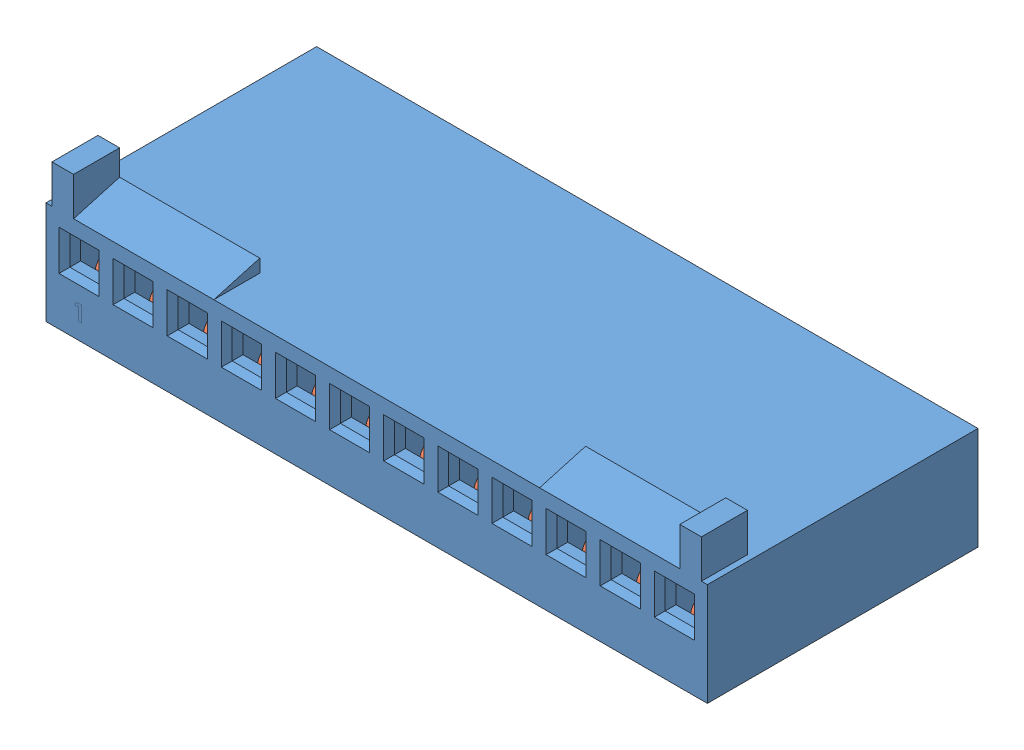
SolidWorks assembly PCB Header Connector 12x1, configuration Default. Lengths in mm.
Overall size (31.04 6.63 12.7).
13 component instances, 2 part files, 5 mates.
Components (placement in the parent):
- PCB Header Female Molex KK 254 12x1 Housing-1: PCB Header Female Molex KK 254 12x1 Housing [Default] at origin size (31.04 6.63 12.7)
- PCB Header Female KK 254 Molex Connector-2: PCB Header Female KK 254 Molex Connector [Default] at (13.97 1.0922 -11.002) size (2.11 3.68 9.73)
- PCB Header Female KK 254 Molex Connector-3: PCB Header Female KK 254 Molex Connector [Default] at (11.43 1.0922 -11.002) size (2.11 3.68 9.73)
- PCB Header Female KK 254 Molex Connector-4: PCB Header Female KK 254 Molex Connector [Default] at (8.89 1.0922 -11.002) size (2.11 3.68 9.73)
- PCB Header Female KK 254 Molex Connector-5: PCB Header Female KK 254 Molex Connector [Default] at (6.35 1.0922 -11.002) size (2.11 3.68 9.73)
- PCB Header Female KK 254 Molex Connector-6: PCB Header Female KK 254 Molex Connector [Default] at (3.81 1.0922 -11.002) size (2.11 3.68 9.73)
- PCB Header Female KK 254 Molex Connector-7: PCB Header Female KK 254 Molex Connector [Default] at (1.27 1.0922 -11.002) size (2.11 3.68 9.73)
- PCB Header Female KK 254 Molex Connector-8: PCB Header Female KK 254 Molex Connector [Default] at (-1.27 1.0922 -11.002) size (2.11 3.68 9.73)
- PCB Header Female KK 254 Molex Connector-9: PCB Header Female KK 254 Molex Connector [Default] at (-3.81 1.0922 -11.002) size (2.11 3.68 9.73)
- PCB Header Female KK 254 Molex Connector-10: PCB Header Female KK 254 Molex Connector [Default] at (-6.35 1.0922 -11.002) size (2.11 3.68 9.73)
- PCB Header Female KK 254 Molex Connector-11: PCB Header Female KK 254 Molex Connector [Default] at (-8.89 1.0922 -11.002) size (2.11 3.68 9.73)
- PCB Header Female KK 254 Molex Connector-12: PCB Header Female KK 254 Molex Connector [Default] at (-11.43 1.0922 -11.002) size (2.11 3.68 9.73)
- PCB Header Female KK 254 Molex Connector-13: PCB Header Female KK 254 Molex Connector [Default] at (-13.97 1.0922 -11.002) size (2.11 3.68 9.73)
Mates (geometry in assembly coordinates):
- Tangent11: tangent anti-aligned: plane of PCB Header Female Molex KK 254 12x1 Housing-1 through (14.732 1.0922 -0.762) normal (0 0 -1); cylinder of PCB Header Female KK 254 Molex Connector-2 through (14.945 1.8122 -1.482) axis (-1 0 0) radius 0.72
- Coincident31: coincident anti-aligned: plane of PCB Header Female Molex KK 254 12x1 Housing-1 through (14.732 1.0922 -12.7) normal (0 1 0); plane of PCB Header Female KK 254 Molex Connector-2 through (14.945 1.0922 -5.232) normal (0 -1 0)
- Parallel21: parallel anti-aligned: plane of PCB Header Female Molex KK 254 12x1 Housing-1 through (14.732 0 0) normal (-1 0 0); plane of PCB Header Female KK 254 Molex Connector-2 through (14.945 1.8122 -1.992) normal (1 0 0)
- Width1: width aligned: plane of PCB Header Female Molex KK 254 12x1 Housing-1 through (14.732 0 0) normal (-1 0 0); plane of PCB Header Female Molex KK 254 12x1 Housing-1 through (13.208 0 0) normal (1 0 0); plane of PCB Header Female KK 254 Molex Connector-2 through (12.995 1.8122 -1.992) normal (-1 0 0); plane of PCB Header Female KK 254 Molex Connector-2 through (14.945 1.8122 -1.992) normal (1 0 0)
- Coincident36: coincident: plane of PCB Header Female Molex KK 254 12x1 Housing-1 through (13.5001 5.0164 -4.572) normal (0 0 1); line of PCB Header Female KK 254 Molex Connector-2 through (14.29 0.7176 -4.572) axis (-1 0 0)
